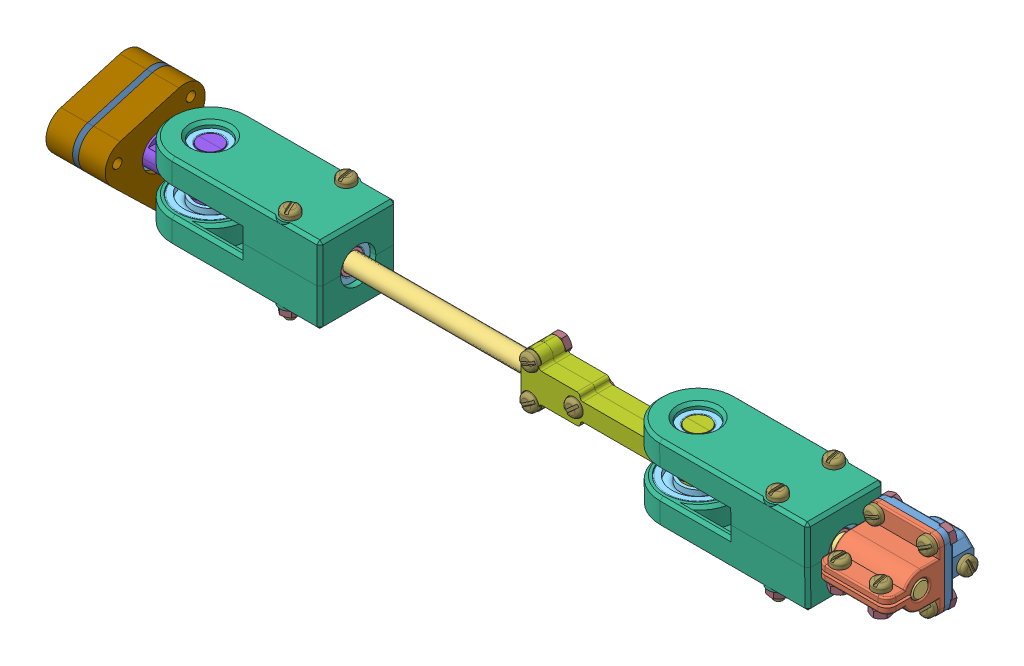
SolidWorks assembly Arm Assembly, configuration Default. Lengths in mm.
Overall size (279.84 48.78 47.27).
60 component instances, 13 part files, 139 mates.
Components (placement in the parent):
- Stepper Shaft Rod Mount - V1-1: Stepper Shaft Rod Mount - V1 [Default] x (-1 0 0) z (0 -1 0) size (24 11 24)
- Rod Holder - V1-1: Rod Holder - V1 [Default] at (12 0 2) x (0 -1 0) z (0 0 -1) size (24 24.06 19.45)
- Arm Rod - V1-1: Arm Rod - V1 [Lower Rod] at (-13 0 8) size (50 6 6)
- Bearing Rod Clamp - V2-1: Bearing Rod Clamp - V2 [Default] at (-26.6 0 8) size (25.8 10 10)
- instrument ball bearing_68_am-1: instrument ball bearing_68_am [AFBMA 12.1.4.1 - 0080-22 - 8,SI,NC,8_68] at (-34.9 0 8) x (1 0 0) z (0 -0.008393 0.999965) size (7 22 22)
- instrument ball bearing_68_am-2: instrument ball bearing_68_am [AFBMA 12.1.4.1 - 0080-22 - 8,SI,NC,8_68] at (-18.7 0 8) x (1 0 0) z (0 -0.008393 0.999965) size (7 22 22)
- Arm Joint - V1-1: Arm Joint - V1 [Default] at (-26.8 -12.9995 7.8909) x (1 0 0) z (0 -0.008393 0.999965) size (63 18.02 26)
- instrument ball bearing_68_am-3: instrument ball bearing_68_am [AFBMA 12.1.4.1 - 0080-22 - 8,SI,NC,8_68] at (-63.3 -7.4997 7.9371) x (0 -0.999965 -0.008393) z (0 -0.008393 0.999965) size (7 22 22)
- instrument ball bearing_68_am-4: instrument ball bearing_68_am [AFBMA 12.1.4.1 - 0080-22 - 8,SI,NC,8_68] at (-63.3 7.4997 8.0629) x (0 0.999965 0.008393) z (0 0.008393 -0.999965) size (7 22 22)
- Arm Joint - V1-2: Arm Joint - V1 [Default] at (-26.8 12.9995 8.1091) x (1 0 0) z (0 0.008393 -0.999965) size (63 18.02 26)
- Arm Bearing Joint Inner - V1-1: Arm Bearing Joint Inner - V1 [Bottom] at (-63.3 0 8) x (-1 -0.000006 0.000733) z (0 -0.999965 -0.008393) size (60 5 22)
- Arm Bearing Joint Inner - V1-2: Arm Bearing Joint Inner - V1 [Top] at (-63.3 0 8) x (-1 -0.000006 0.000733) z (0 0.999965 0.008393) size (60 5 22)
- Arm Rod - V1-2: Arm Rod - V1 [Upper Rod] at (-153.3 -0.0006 8.066) x (1 0.000006 -0.000733) z (0.000733 -0.008393 0.999965) size (100 6 6)
- Bearing Rod Clamp - V2-2: Bearing Rod Clamp - V2 [Default] at (-191.9 -0.0008 8.0942) x (1 0.000006 -0.000733) z (0.000733 -0.008393 0.999965) size (25.8 10 10)
- Arm Joint - V1-3: Arm Joint - V1 [Default] at (-191.9 12.9992 8.1007) x (1 0.000006 -0.000733) z (-0.000733 0.000495 -1) size (63 18.02 26)
- Arm Joint - V1-4: Arm Joint - V1 [Default] at (-191.8999 -13.0008 8.0878) x (1 0.000006 -0.000733) z (0.000733 -0.000495 1) size (63 18.02 26)
- instrument ball bearing_68_am-5: instrument ball bearing_68_am [AFBMA 12.1.4.1 - 0080-22 - 8,SI,NC,8_68] at (-200 -0.0008 8.1002) x (1 0.000006 -0.000733) z (0.000733 -0.000495 1) size (7 22 22)
- instrument ball bearing_68_am-6: instrument ball bearing_68_am [AFBMA 12.1.4.1 - 0080-22 - 8,SI,NC,8_68] at (-184 -0.0007 8.0885) x (1 0.000006 -0.000733) z (0.000733 -0.000495 1) size (7 22 22)
- instrument ball bearing_68_am-7: instrument ball bearing_68_am [AFBMA 12.1.4.1 - 0080-22 - 8,SI,NC,8_68] at (-228.3999 -7.501 8.1173) x (0.000006 -1 -0.000495) z (0.000733 -0.000495 1) size (7 22 22)
- instrument ball bearing_68_am-8: instrument ball bearing_68_am [AFBMA 12.1.4.1 - 0080-22 - 8,SI,NC,8_68] at (-228.4 7.499 8.1247) x (-0.000006 1 0.000495) z (-0.000733 0.000495 -1) size (7 22 22)
- End Effector Mount Inner - V1-1: End Effector Mount Inner - V1 [Bottom] at (-228.4 -0.001 8.121) x (-0.999996 -0.000007 0.002957) z (0.000006 -1 -0.000495) size (40 5 22)
- End Effector Mount Inner - V1-2: End Effector Mount Inner - V1 [Top] at (-228.4 -0.001 8.121) x (-0.999996 -0.000007 0.002957) z (-0.000006 1 0.000495) size (40 5 22)
- End Effector Mount - V1-1: End Effector Mount - V1 [Default] at (-245.3999 -0.0011 8.1713) x (-0.002064 0.717902 -0.696141) z (0.002118 0.696144 0.717899) size (32 9 34.78)
- End Effector Mount - V1-2: End Effector Mount - V1 [Default] at (-265.3998 -0.0013 8.2304) x (-0.000802 -0.96183 -0.273648) z (0.002847 -0.273649 0.961825) size (32 9 34.78)
- End Effector Mount Divider - V1-1: End Effector Mount Divider - V1 [Default] at (-256.3998 -0.0012 8.2038) x (-0.000802 -0.96183 -0.273648) z (0.002847 -0.273649 0.961825) size (32 2 34.78)
- End Effector Mount Clip - V1-1: End Effector Mount Clip - V1 [Default] at (-254.5998 -0.0012 8.1985) x (0.000006 -1 -0.000495) z (-0.002957 0.000495 -0.999996) size (10 1.8 9.18)
- instrument ball bearing_68_am-9: instrument ball bearing_68_am [AFBMA 12.1.4.1 - 0080-22 - 8,SI,NC,8_68] at (-250.8999 -0.0012 8.1875) x (0.999996 0.000007 -0.002957) z (0.002118 0.696144 0.717899) size (7 22 22)
- instrument ball bearing_68_am-10: instrument ball bearing_68_am [AFBMA 12.1.4.1 - 0080-22 - 8,SI,NC,8_68] at (-259.8998 -0.0012 8.2141) x (-0.999996 -0.000007 0.002957) z (0.002847 -0.273649 0.961825) size (7 22 22)
- pan slot head_am-23: pan slot head_am [B18.6.7M - M3 x 0.5 x 30 Slotted PHMS --30C] at (-26.8 15.3197 17.6289) x (0 -0.999965 -0.008393) z (0 -0.008393 0.999965) size (32.48 5.6 5.6)
- pan slot head_am-24: pan slot head_am [B18.6.7M - M3 x 0.5 x 30 Slotted PHMS --30C] at (-26.8 15.4792 -1.3704) x (0 -0.999965 -0.008393) z (0.188455 -0.008242 0.982047) size (32.48 5.6 5.6)
- pan slot head_am-26: pan slot head_am [B18.6.7M - M3 x 0.5 x 6 Slotted PHMS --6C] at (-9 9 4.4) x (0 0 -1) z (0.923728 0.383049 0) size (8.48 5.6 5.6)
- pan slot head_am-27: pan slot head_am [B18.6.7M - M3 x 0.5 x 6 Slotted PHMS --6C] at (9 9 4.4) x (0 0 -1) z (0.85131 0.524663 0) size (8.48 5.6 5.6)
- pan slot head_am-29: pan slot head_am [B18.6.7M - M3 x 0.5 x 6 Slotted PHMS --6C] at (-9 -9 4.4) x (0 0 -1) z (0.777574 0.628792 0) size (8.48 5.6 5.6)
- pan slot head_am-31: pan slot head_am [B18.6.7M - M3 x 0.5 x 6 Slotted PHMS --6C] at (9 -9 4.4) x (0 0 -1) z (0.715577 0.698533 0) size (8.48 5.6 5.6)
- pan slot head_am-33: pan slot head_am [B18.6.7M - M3 x 0.5 x 8 Slotted PHMS --8C] at (-7 4.9 16.4544) x (0 -1 0) z (0 0 1) size (10.48 5.6 5.6)
- pan slot head_am-34: pan slot head_am [B18.6.7M - M3 x 0.5 x 8 Slotted PHMS --8C] at (7 4.9 16.4544) x (0 -1 0) z (0.188455 0 0.982082) size (10.48 5.6 5.6)
- pan slot head_am-36: pan slot head_am [B18.6.7M - M3 x 0.5 x 10 Slotted PHMS --10C] at (-115.2953 5.9458 14.4882) x (-0.000733 0.008393 -0.999965) z (0.917109 0.398627 0.002673) size (12.48 5.6 5.6)
- pan slot head_am-37: pan slot head_am [B18.6.7M - M3 x 0.5 x 10 Slotted PHMS --10C] at (-115.2953 -6.0538 14.3875) x (-0.000733 0.008393 -0.999965) z (0.83264 0.553799 0.004038) size (12.48 5.6 5.6)
- pan slot head_am-39: pan slot head_am [B18.6.7M - M3 x 0.5 x 10 Slotted PHMS --10C] at (-100.2953 -0.0539 14.4269) x (-0.000733 0.008393 -0.999965) z (0.746211 0.665691 0.00504) size (12.48 5.6 5.6)
- pan slot head_am-41: pan slot head_am [B18.6.7M - M3 x 0.5 x 10 Slotted PHMS --10C] at (-63.2953 -0.0537 14.3998) x (-0.000733 0.008393 -0.999965) z (0.67374 0.738946 0.005708) size (12.48 5.6 5.6)
- pan slot head_am-43: pan slot head_am [B18.6.7M - M3 x 0.5 x 30 Slotted PHMS --30C] at (-191.907 15.4039 -1.3981) x (0.000006 -1 -0.000495) z (0.153233 -0.000489 0.98819) size (32.48 5.6 5.6)
- pan slot head_am-45: pan slot head_am [B18.6.7M - M3 x 0.5 x 30 Slotted PHMS --30C] at (-191.8931 15.3945 17.6019) x (0.000006 -1 -0.000495) z (0.402815 -0.000451 0.915281) size (32.48 5.6 5.6)
- hex nut style 1_am-1: hex nut style 1_am [B18.2.4.1M - Hex nut, Style 1,  M3 x 0.5 --D-N] at (-7 -4.9 16.4544) x (1 0 0) z (0 -1 0) size (5.5 6.35 2.4)
- hex nut style 1_am-2: hex nut style 1_am [B18.2.4.1M - Hex nut, Style 1,  M3 x 0.5 --D-N] at (7 -4.9 16.4544) x (0.982082 0 -0.188455) z (0 -1 0) size (5.5 6.35 2.4)
- hex nut style 1_am-4: hex nut style 1_am [B18.2.4.1M - Hex nut, Style 1,  M3 x 0.5 --D-N] at (-26.8 -15.4792 17.3704) x (0.918365 0.003321 -0.39572) z (0 -0.999965 -0.008393) size (5.5 6.35 2.4)
- hex nut style 1_am-6: hex nut style 1_am [B18.2.4.1M - Hex nut, Style 1,  M3 x 0.5 --D-N] at (-26.8 -15.3197 -1.6289) x (0.8 0.005036 -0.599979) z (0 -0.999965 -0.008393) size (5.5 6.35 2.4)
- hex nut style 1_am-8: hex nut style 1_am [B18.2.4.1M - Hex nut, Style 1,  M3 x 0.5 --D-N] at (-191.8929 -15.4055 17.5866) x (0.628342 0.000389 -0.777937) z (0.000006 -1 -0.000495) size (5.5 6.35 2.4)
- hex nut style 1_am-10: hex nut style 1_am [B18.2.4.1M - Hex nut, Style 1,  M3 x 0.5 --D-N] at (-191.9068 -15.3961 -1.4134) x (0.466897 0.000441 -0.884312) z (0.000006 -1 -0.000495) size (5.5 6.35 2.4)
- hex nut style 1_am-12: hex nut style 1_am [B18.2.4.1M - Hex nut, Style 1,  M3 x 0.5 --D-N] at (-9 -9 -2) x (-0.707107 0.707107 0) z (0 0 1) size (5.5 6.35 2.4)
- hex nut style 1_am-13: hex nut style 1_am [B18.2.4.1M - Hex nut, Style 1,  M3 x 0.5 --D-N] at (9 -9 -2) x (-0.965926 0.258819 0) z (0 0 1) size (5.5 6.35 2.4)
- hex nut style 1_am-15: hex nut style 1_am [B18.2.4.1M - Hex nut, Style 1,  M3 x 0.5 --D-N] at (-9 9 -2) x (0.707107 0.707107 0) z (0 0 1) size (5.5 6.35 2.4)
- hex nut style 1_am-17: hex nut style 1_am [B18.2.4.1M - Hex nut, Style 1,  M3 x 0.5 --D-N] at (9 9 -2) x (-0.258819 -0.965926 0) z (0 0 1) size (5.5 6.35 2.4)
- hex nut style 1_am-19: hex nut style 1_am [B18.2.4.1M - Hex nut, Style 1,  M3 x 0.5 --D-N] at (-115.3029 -5.9665 3.9879) x (-0.866025 0.499977 0.004831) z (0.000733 -0.008393 0.999965) size (5.5 6.35 2.4)
- hex nut style 1_am-21: hex nut style 1_am [B18.2.4.1M - Hex nut, Style 1,  M3 x 0.5 --D-N] at (-115.3029 6.033 4.0886) x (0.866025 -0.499977 -0.004831) z (0.000733 -0.008393 0.999965) size (5.5 6.35 2.4)
- hex nut style 1_am-23: hex nut style 1_am [B18.2.4.1M - Hex nut, Style 1,  M3 x 0.5 --D-N] at (-100.3029 0.0333 4.0273) x (0.5 -0.865992 -0.007635) z (0.000733 -0.008393 0.999965) size (5.5 6.35 2.4)
- hex nut style 1_am-25: hex nut style 1_am [B18.2.4.1M - Hex nut, Style 1,  M3 x 0.5 --D-N] at (-63.3029 0.0336 4.0001) x (-0.5 -0.865998 -0.006902) z (0.000733 -0.008393 0.999965) size (5.5 6.35 2.4)
- hex nut style 1_am-27: hex nut style 1_am [B18.2.4.1M - Hex nut, Style 1,  M3 x 0.5 --D-N] at (6.2 0 -7) x (0 -0.866025 0.5) z (1 0 0) size (5.5 6.35 2.4)
- pan slot head_am-48: pan slot head_am [B18.6.7M - M3 x 0.5 x 10 Slotted PHMS --10C] at (14.3 0 -7) x (-1 0 0) z (0 -0.924225 -0.381849) size (12.48 5.6 5.6)
- pan slot head_am-49: pan slot head_am [B18.6.7M - M3 x 0.5 x 10 Slotted PHMS --10N] at (-228.381 -0.0042 14.521) x (-0.002957 0.000495 -0.999996) z (0.999996 0.000497 -0.002957) size (12.4 5.6 5.6)
- hex nut style 1_am-29: hex nut style 1_am [B18.2.4.1M - Hex nut, Style 1,  M3 x 0.5 --D-N] at (-228.4189 0.0022 1.721) x (-0.999996 -0.000007 0.002957) z (-0.002957 0.000495 -0.999996) size (5.5 6.35 2.4)
Mates (geometry in assembly coordinates):
- Coincident4: coincident: plane of Stepper Shaft Rod Mount - V1-1 through (0 0 0) normal (0 0 -1); plane of assembly through (0 0 0) normal (0 0 1)
- Coincident5: coincident: plane of Stepper Shaft Rod Mount - V1-1 through (0 0 0) normal (0 -1 0); plane of assembly through (0 0 0) normal (0 1 0)
- Coincident9: coincident anti-aligned: plane of Stepper Shaft Rod Mount - V1-1 through (0 0 0) normal (-1 0 0); plane of assembly through (0 0 0) normal (1 0 0)
- Coincident10: coincident anti-aligned: plane of Stepper Shaft Rod Mount - V1-1 through (0 0 0) normal (0 0 1); plane of Rod Holder - V1-1 through (12 0 0) normal (0 0 -1)
- Concentric2: concentric: cylinder of Stepper Shaft Rod Mount - V1-1 through (-9 -9 0) axis (0 0 -1) radius 1.6; cylinder of Rod Holder - V1-1 through (-9 -9 -1) axis (0 0 1) radius 1.6
- Concentric3: concentric: cylinder of Stepper Shaft Rod Mount - V1-1 through (9 9 0) axis (0 0 -1) radius 1.6; cylinder of Rod Holder - V1-1 through (9 9 -1) axis (0 0 1) radius 1.6
- Concentric4: concentric: cylinder of Rod Holder - V1-1 through (-12 0 8) axis (1 0 0) radius 3; cylinder of Arm Rod - V1-1 through (12 0 8) axis (-1 0 0) radius 3
- Coincident11: coincident: plane of Rod Holder - V1-1 through (12 0 8) normal (1 0 0); plane of Arm Rod - V1-1 through (12 0 8) normal (1 0 0)
- Coincident12: coincident anti-aligned: plane of Arm Rod - V1-1 through (-38 0 8) normal (-1 0 0); plane of Bearing Rod Clamp - V2-1 through (-38 0 8) normal (1 0 0)
- Concentric5: concentric aligned: cylinder of Arm Rod - V1-1 through (12 0 8) axis (-1 0 0) radius 3; cylinder of Bearing Rod Clamp - V2-1 through (-38 0 8) axis (-1 0 0) radius 3.1
- Concentric6: concentric anti-aligned: cylinder of instrument ball bearing_68_am-1 through (-55.5375 0 8) axis (1 0 0) radius 11; cylinder of Arm Joint - V1-1 through (-31.2 0 8) axis (-1 0 0) radius 11.1
- Concentric7: concentric aligned: cylinder of instrument ball bearing_68_am-2 through (-39.3375 0 8) axis (1 0 0) radius 11; cylinder of Arm Joint - V1-1 through (-22.4 0 8) axis (1 0 0) radius 11.1
- Coincident13: coincident anti-aligned: plane of instrument ball bearing_68_am-2 through (-15.2 10.6996 8.0898) normal (1 0 0); plane of Arm Joint - V1-1 through (-15.2 0 8) normal (-1 0 0)
- Coincident14: coincident anti-aligned: plane of instrument ball bearing_68_am-1 through (-38.4 8.8997 8.0747) normal (-1 0 0); plane of Arm Joint - V1-1 through (-38.4 0 8) normal (1 0 0)
- Concentric8: concentric anti-aligned: cylinder of Bearing Rod Clamp - V2-1 through (-38 0 8) axis (-1 0 0) radius 3.9; cylinder of instrument ball bearing_68_am-1 through (-55.5375 0 8) axis (1 0 0) radius 4
- Coincident15: coincident aligned: plane of Bearing Rod Clamp - V2-1 through (-15.2 0 4.1) normal (1 0 0); plane of instrument ball bearing_68_am-2 through (-15.2 4.2998 8.0361) normal (1 0 0)
- Concentric9: concentric anti-aligned: cylinder of Arm Joint - V1-1 through (-63.3 -10.9996 7.9077) axis (0 0.999965 0.008393) radius 11.1; cylinder of instrument ball bearing_68_am-3 through (-63.3 13.137 8.1103) axis (0 -0.999965 -0.008393) radius 11
- Coincident16: coincident anti-aligned: plane of Arm Joint - V1-1 through (-63.3 -10.9996 7.9077) normal (0 0.999965 0.008393); plane of instrument ball bearing_68_am-3 through (-52.6 -10.9996 7.9077) normal (0 -0.999965 -0.008393)
- Concentric10: concentric anti-aligned: cylinder of instrument ball bearing_68_am-4 through (-63.3 -13.137 7.8897) axis (0 0.999965 0.008393) radius 11; cylinder of Arm Joint - V1-2 through (-63.3 10.9996 8.0923) axis (0 -0.999965 -0.008393) radius 11.1
- Coincident17: coincident anti-aligned: plane of instrument ball bearing_68_am-4 through (-52.6 10.9996 8.0923) normal (0 0.999965 0.008393); plane of Arm Joint - V1-2 through (-63.3 10.9996 8.0923) normal (0 -0.999965 -0.008393)
- Coincident18: coincident anti-aligned: plane of Arm Bearing Joint Inner - V1-1 through (-63.3 0 8) normal (0.000733 -0.008393 0.999965); plane of Arm Bearing Joint Inner - V1-2 through (-63.3 0 8) normal (-0.000733 0.008393 -0.999965)
- Coincident19: coincident aligned: plane of Arm Bearing Joint Inner - V1-1 through (-118.3 -0.0003 8.0403) normal (-1 -0.000006 0.000733); plane of Arm Bearing Joint Inner - V1-2 through (-118.3 -0.0003 8.0403) normal (-1 -0.000006 0.000733)
- Coincident20: coincident aligned: plane of Arm Bearing Joint Inner - V1-1 through (-58.3037 3.0419 3.0217) normal (0 0.999965 0.008393); plane of Arm Bearing Joint Inner - V1-2 through (-58.2963 2.958 13.0213) normal (0 0.999965 0.008393)
- Concentric11: concentric anti-aligned: cylinder of instrument ball bearing_68_am-3 through (-63.3 13.137 8.1103) axis (0 -0.999965 -0.008393) radius 4; cylinder of Arm Bearing Joint Inner - V1-2 through (-63.3 -10.9996 7.9077) axis (0 0.999965 0.008393) radius 3.9
- Coincident21: coincident anti-aligned: plane of instrument ball bearing_68_am-3 through (-57.2 -3.9999 7.9664) normal (0 0.999965 0.008393); plane of Arm Bearing Joint Inner - V1-1 through (-63.3 -3.9999 7.9664) normal (0 -0.999965 -0.008393)
- Coincident22: coincident aligned: plane of Arm Joint - V1-1 through (-40.3 -11.1087 20.9072) normal (0 -0.008393 0.999965); plane of Arm Joint - V1-2 through (-40.3 10.8905 21.0919) normal (0 -0.008393 0.999965)
- Coincident23: coincident aligned: plane of Arm Joint - V1-1 through (-13.3 -11.1087 20.9072) normal (1 0 0); plane of Arm Joint - V1-2 through (-13.3 11.1087 -4.9072) normal (1 0 0)
- Coincident24: coincident anti-aligned: plane of Arm Joint - V1-1 through (-26.8 0 8) normal (0 0.999965 0.008393); plane of Arm Joint - V1-2 through (-26.8 0 8) normal (0 -0.999965 -0.008393)
- Concentric12: concentric aligned: cylinder of Arm Bearing Joint Inner - V1-2 through (-103.3 -0.0002 8.0293) axis (-1 -0.000006 0.000733) radius 3; cylinder of Arm Rod - V1-2 through (-103.3 -0.0002 8.0293) axis (-1 -0.000006 0.000733) radius 3
- Coincident25: coincident anti-aligned: plane of Arm Bearing Joint Inner - V1-2 through (-103.3 -0.0002 8.0293) normal (-1 -0.000006 0.000733); plane of Arm Rod - V1-2 through (-103.3 -0.0002 8.0293) normal (1 0.000006 -0.000733)
- Concentric13: concentric aligned: cylinder of Arm Rod - V1-2 through (-103.3 -0.0002 8.0293) axis (-1 -0.000006 0.000733) radius 3; cylinder of Bearing Rod Clamp - V2-2 through (-203.3 -0.0009 8.1026) axis (-1 -0.000006 0.000733) radius 3.1
- Coincident26: coincident anti-aligned: plane of Arm Rod - V1-2 through (-203.3 -0.0009 8.1026) normal (-1 -0.000006 0.000733); plane of Bearing Rod Clamp - V2-2 through (-203.3 -0.0009 8.1026) normal (1 0.000006 -0.000733)
- Concentric19: concentric anti-aligned: cylinder of Arm Joint - V1-4 through (-196.3 -0.0008 8.0975) axis (-1 -0.000006 0.000733) radius 11.1; cylinder of instrument ball bearing_68_am-5 through (-220.6375 -0.001 8.1153) axis (1 0.000006 -0.000733) radius 11
- Coincident35: coincident anti-aligned: plane of Arm Joint - V1-4 through (-203.5 -0.0009 8.1027) normal (1 0.000006 -0.000733); plane of instrument ball bearing_68_am-5 through (-203.5 8.8991 8.1071) normal (-1 -0.000006 0.000733)
- Concentric20: concentric aligned: cylinder of Arm Joint - V1-4 through (-187.5 -0.0008 8.091) axis (1 0.000006 -0.000733) radius 11.1; cylinder of instrument ball bearing_68_am-6 through (-204.6375 -0.0009 8.1036) axis (1 0.000006 -0.000733) radius 11
- Coincident36: coincident anti-aligned: plane of Arm Joint - V1-4 through (-187.5 -0.0008 8.091) normal (1 0.000006 -0.000733); plane of instrument ball bearing_68_am-6 through (-187.5 8.8992 8.0954) normal (-1 -0.000006 0.000733)
- Concentric21: concentric anti-aligned: cylinder of Arm Joint - V1-4 through (-228.3999 -11.001 8.1155) axis (-0.000006 1 0.000495) radius 11.1; cylinder of instrument ball bearing_68_am-7 through (-228.4 13.1365 8.1275) axis (0.000006 -1 -0.000495) radius 11
- Coincident37: coincident anti-aligned: plane of Arm Joint - V1-4 through (-228.3999 -11.001 8.1155) normal (-0.000006 1 0.000495); plane of instrument ball bearing_68_am-7 through (-217.6999 -11.0009 8.1077) normal (0.000006 -1 -0.000495)
- Concentric22: concentric anti-aligned: cylinder of Arm Joint - V1-3 through (-228.4 10.999 8.1264) axis (0.000006 -1 -0.000495) radius 11.1; cylinder of instrument ball bearing_68_am-8 through (-228.3999 -13.1385 8.1145) axis (-0.000006 1 0.000495) radius 11
- Coincident38: coincident anti-aligned: plane of Arm Joint - V1-3 through (-228.4 10.999 8.1264) normal (0.000006 -1 -0.000495); plane of instrument ball bearing_68_am-8 through (-217.7 10.999 8.1186) normal (-0.000006 1 0.000495)
- Concentric23: concentric anti-aligned: cylinder of Bearing Rod Clamp - V2-2 through (-203.3 -0.0009 8.1026) axis (-1 -0.000006 0.000733) radius 3.9; cylinder of instrument ball bearing_68_am-5 through (-220.6375 -0.001 8.1153) axis (1 0.000006 -0.000733) radius 4
- Coincident39: coincident aligned: plane of Bearing Rod Clamp - V2-2 through (-180.5028 0.032 4.186) normal (1 0.000006 -0.000733); plane of instrument ball bearing_68_am-6 through (-180.5 4.2993 8.088) normal (1 0.000006 -0.000733)
- Coincident40: coincident anti-aligned: plane of End Effector Mount Inner - V1-1 through (-228.4 -0.001 8.121) normal (0.002957 -0.000495 0.999996); plane of End Effector Mount Inner - V1-2 through (-228.4 -0.001 8.121) normal (-0.002957 0.000495 -0.999996)
- Coincident41: coincident aligned: plane of End Effector Mount Inner - V1-1 through (-223.4147 -2.9985 3.1047) normal (0.000006 -1 -0.000495); plane of End Effector Mount Inner - V1-2 through (-223.3852 -3.0035 13.1047) normal (0.000006 -1 -0.000495)
- Coincident42: coincident aligned: plane of End Effector Mount Inner - V1-1 through (-263.3998 -0.0013 8.2245) normal (-0.999996 -0.000007 0.002957); plane of End Effector Mount Inner - V1-2 through (-263.3998 -0.0013 8.2245) normal (-0.999996 -0.000007 0.002957)
- Concentric24: concentric anti-aligned: cylinder of instrument ball bearing_68_am-7 through (-228.4 13.1365 8.1275) axis (0.000006 -1 -0.000495) radius 4; cylinder of End Effector Mount Inner - V1-2 through (-228.3999 -11.001 8.1155) axis (-0.000006 1 0.000495) radius 3.9
- Coincident43: coincident anti-aligned: plane of instrument ball bearing_68_am-7 through (-222.2999 -4.001 8.1145) normal (-0.000006 1 0.000495); plane of End Effector Mount Inner - V1-2 through (-228.3999 -4.001 8.119) normal (0.000006 -1 -0.000495)
- Coincident44: coincident aligned: plane of Arm Joint - V1-3 through (-205.4096 11.0056 -4.8904) normal (-0.000733 0.000495 -1); plane of Arm Joint - V1-4 through (-205.4094 -10.9944 -4.9013) normal (-0.000733 0.000495 -1)
- Coincident45: coincident aligned: plane of Arm Joint - V1-3 through (-178.4096 11.0057 -4.9102) normal (1 0.000006 -0.000733); plane of Arm Joint - V1-4 through (-178.3904 -11.0071 21.0789) normal (1 0.000006 -0.000733)
- Coincident46: coincident anti-aligned: plane of Arm Joint - V1-3 through (-191.9 -0.0008 8.0942) normal (0.000006 -1 -0.000495); plane of Arm Joint - V1-4 through (-191.9 -0.0008 8.0942) normal (-0.000006 1 0.000495)
- Concentric25: concentric anti-aligned: cylinder of End Effector Mount Inner - V1-2 through (-263.3998 -0.0013 8.2245) axis (0.999996 0.000007 -0.002957) radius 3.9; cylinder of End Effector Mount Clip - V1-1 through (-254.5998 -0.0012 8.1985) axis (-0.999996 -0.000007 0.002957) radius 4
- Parallel4: parallel anti-aligned: plane of End Effector Mount Inner - V1-2 through (-254.385 -2.9037 13.1964) normal (0.000006 -1 -0.000495); plane of End Effector Mount Clip - V1-1 through (-254.592 -3.0025 10.8427) normal (-0.000006 1 0.000495)
- Coincident48: coincident anti-aligned: plane of End Effector Mount Inner - V1-2 through (-256.385 -2.9037 13.2023) normal (0.999996 0.000007 -0.002957); plane of End Effector Mount Clip - V1-1 through (-256.3998 -0.0012 8.2038) normal (-0.999996 -0.000007 0.002957)
- Concentric26: concentric anti-aligned: cylinder of End Effector Mount - V1-1 through (-247.3999 -0.0012 8.1772) axis (-0.999996 -0.000007 0.002957) radius 11.1; cylinder of instrument ball bearing_68_am-9 through (-271.5373 -0.0013 8.2486) axis (0.999996 0.000007 -0.002957) radius 11
- Coincident49: coincident anti-aligned: plane of End Effector Mount - V1-1 through (-247.3999 -0.0012 8.1772) normal (-0.999996 -0.000007 0.002957); plane of instrument ball bearing_68_am-9 through (-247.422 7.6804 0.7285) normal (0.999996 0.000007 -0.002957)
- Concentric27: concentric anti-aligned: cylinder of End Effector Mount - V1-2 through (-263.3998 -0.0013 8.2245) axis (0.999996 0.000007 -0.002957) radius 11.1; cylinder of instrument ball bearing_68_am-10 through (-239.2624 -0.0011 8.1531) axis (-0.999996 -0.000007 0.002957) radius 11
- Coincident50: coincident anti-aligned: plane of End Effector Mount - V1-2 through (-263.3998 -0.0013 8.2245) normal (0.999996 0.000007 -0.002957); plane of instrument ball bearing_68_am-10 through (-263.4084 -10.2928 5.2965) normal (-0.999996 -0.000007 0.002957)
- Concentric28: concentric anti-aligned: cylinder of End Effector Mount - V1-2 through (-265.3998 -0.0013 8.2304) axis (0.999996 0.000007 -0.002957) radius 6; cylinder of End Effector Mount Divider - V1-1 through (-254.3998 -0.0012 8.1979) axis (-0.999996 -0.000007 0.002957) radius 6
- Coincident51: coincident aligned: plane of End Effector Mount - V1-2 through (-256.4207 -25.0088 1.089) normal (-0.002866 -0.243928 -0.969789); plane of End Effector Mount Divider - V1-1 through (-254.4207 -25.0088 1.083) normal (-0.002866 -0.243928 -0.969789)
- Coincident52: coincident anti-aligned: plane of End Effector Mount - V1-2 through (-256.3998 -0.0012 8.2038) normal (0.999996 0.000007 -0.002957); plane of End Effector Mount Divider - V1-1 through (-256.3998 -0.0012 8.2038) normal (-0.999996 -0.000007 0.002957)
- Coincident53: coincident anti-aligned: plane of End Effector Mount - V1-1 through (-254.3998 -0.0012 8.1979) normal (-0.999996 -0.000007 0.002957); plane of End Effector Mount Divider - V1-1 through (-254.3998 -0.0012 8.1979) normal (0.999996 0.000007 -0.002957)
- Concentric29: concentric anti-aligned: cylinder of End Effector Mount - V1-1 through (-245.3999 -0.0011 8.1713) axis (-0.999996 -0.000007 0.002957) radius 6; cylinder of End Effector Mount - V1-2 through (-265.3998 -0.0013 8.2304) axis (0.999996 0.000007 -0.002957) radius 6
- Coincident54: coincident aligned: plane of End Effector Mount - V1-1 through (-254.4535 18.6642 -9.9018) normal (-0.002866 -0.243928 -0.969789); plane of End Effector Mount - V1-2 through (-256.4207 -25.0088 1.089) normal (-0.002866 -0.243928 -0.969789)
- Concentric30: concentric aligned: cylinder of End Effector Mount Inner - V1-2 through (-263.3998 -0.0013 8.2245) axis (0.999996 0.000007 -0.002957) radius 3.9; cylinder of instrument ball bearing_68_am-9 through (-271.5373 -0.0013 8.2486) axis (0.999996 0.000007 -0.002957) radius 4
- Coincident55: coincident aligned: plane of End Effector Mount Inner - V1-2 through (-263.3998 -0.0013 8.2245) normal (-0.999996 -0.000007 0.002957); plane of instrument ball bearing_68_am-10 through (-263.4033 -4.1371 7.0478) normal (-0.999996 -0.000007 0.002957)
- Concentric65: concentric anti-aligned: cylinder of Arm Joint - V1-2 through (-26.8 12.9198 17.6088) axis (0 -0.999965 -0.008393) radius 1.6; cylinder of pan slot head_am-23 through (-26.8 40.7188 17.8421) axis (0 0.999965 0.008393) radius 1.5
- Coincident90: coincident anti-aligned: plane of Arm Joint - V1-2 through (-26.8 12.9995 8.1091) normal (0 0.999965 0.008393); plane of pan slot head_am-23 through (-25.3 12.9198 17.6088) normal (0 -0.999965 -0.008393)
- Concentric66: concentric anti-aligned: cylinder of Arm Joint - V1-2 through (-26.8 13.0793 -1.3906) axis (0 -0.999965 -0.008393) radius 1.6; cylinder of pan slot head_am-24 through (-26.8 40.8783 -1.1572) axis (0 0.999965 0.008393) radius 1.5
- Coincident91: coincident anti-aligned: plane of Arm Joint - V1-2 through (-26.8 12.9995 8.1091) normal (0 0.999965 0.008393); plane of pan slot head_am-24 through (-25.3269 13.0816 -1.6732) normal (0 -0.999965 -0.008393)
- Concentric67: concentric aligned: cylinder of Rod Holder - V1-1 through (-9 9 -1) axis (0 0 1) radius 1.6; cylinder of pan slot head_am-26 through (-9 9 29.8) axis (0 0 1) radius 1.5
- Coincident92: coincident anti-aligned: plane of Rod Holder - V1-1 through (12 0 2) normal (0 0 1); plane of pan slot head_am-26 through (-9.5746 10.3856 2) normal (0 0 -1)
- Concentric68: concentric aligned: cylinder of Rod Holder - V1-1 through (9 9 -1) axis (0 0 1) radius 1.6; cylinder of pan slot head_am-27 through (9 9 29.8) axis (0 0 1) radius 1.5
- Coincident93: coincident anti-aligned: plane of Rod Holder - V1-1 through (12 0 2) normal (0 0 1); plane of pan slot head_am-27 through (8.213 10.277 2) normal (0 0 -1)
- Concentric69: concentric aligned: cylinder of Rod Holder - V1-1 through (-9 -9 -1) axis (0 0 1) radius 1.6; cylinder of pan slot head_am-29 through (-9 -9 29.8) axis (0 0 1) radius 1.5
- Coincident94: coincident anti-aligned: plane of Rod Holder - V1-1 through (12 0 2) normal (0 0 1); plane of pan slot head_am-29 through (-9.9432 -7.8336 2) normal (0 0 -1)
- Concentric70: concentric aligned: cylinder of Rod Holder - V1-1 through (9 -9 -1) axis (0 0 1) radius 1.6; cylinder of pan slot head_am-31 through (9 -9 29.8) axis (0 0 1) radius 1.5
- Coincident95: coincident anti-aligned: plane of Rod Holder - V1-1 through (12 0 2) normal (0 0 1); plane of pan slot head_am-31 through (7.9522 -7.9266 2) normal (0 0 -1)
- Concentric71: concentric anti-aligned: cylinder of Rod Holder - V1-1 through (-7 6 16.4544) axis (0 -1 0) radius 1.6; cylinder of pan slot head_am-33 through (-7 30.3 16.4544) axis (0 1 0) radius 1.5
- Coincident96: coincident anti-aligned: plane of Rod Holder - V1-1 through (-12 2.5 13.4544) normal (0 1 0); plane of pan slot head_am-33 through (-5.5 2.5 16.4544) normal (0 -1 0)
- Concentric72: concentric anti-aligned: cylinder of Rod Holder - V1-1 through (7 6 16.4544) axis (0 -1 0) radius 1.6; cylinder of pan slot head_am-34 through (7 30.3 16.4544) axis (0 1 0) radius 1.5
- Coincident97: coincident anti-aligned: plane of Rod Holder - V1-1 through (-12 2.5 13.4544) normal (0 1 0); plane of pan slot head_am-34 through (8.4731 2.5 16.1717) normal (0 -1 0)
- Concentric73: concentric anti-aligned: cylinder of Arm Bearing Joint Inner - V1-2 through (-115.2963 5.9575 13.0883) axis (-0.000733 0.008393 -0.999965) radius 1.6; cylinder of pan slot head_am-36 through (-115.2767 5.7326 39.8873) axis (0.000733 -0.008393 0.999965) radius 1.5
- Coincident98: coincident anti-aligned: plane of Arm Bearing Joint Inner - V1-2 through (-115.2971 5.9659 12.0883) normal (0.000733 -0.008393 0.999965); plane of pan slot head_am-36 through (-115.895 7.3415 12.1003) normal (-0.000733 0.008393 -0.999965)
- Concentric74: concentric anti-aligned: cylinder of Arm Bearing Joint Inner - V1-2 through (-115.2963 -6.0421 12.9876) axis (-0.000733 0.008393 -0.999965) radius 1.6; cylinder of pan slot head_am-37 through (-115.2767 -6.267 39.7866) axis (0.000733 -0.008393 0.999965) radius 1.5
- Coincident99: coincident anti-aligned: plane of Arm Bearing Joint Inner - V1-2 through (-115.2971 -6.0337 11.9876) normal (0.000733 -0.008393 0.999965); plane of pan slot head_am-37 through (-116.1278 -4.7848 11.9987) normal (-0.000733 0.008393 -0.999965)
- Concentric75: concentric anti-aligned: cylinder of Arm Bearing Joint Inner - V1-2 through (-100.2963 -0.0422 13.0269) axis (-0.000733 0.008393 -0.999965) radius 1.6; cylinder of pan slot head_am-39 through (-100.2767 -0.2671 39.826) axis (0.000733 -0.008393 0.999965) radius 1.5
- Coincident100: coincident anti-aligned: plane of Arm Bearing Joint Inner - V1-2 through (-100.2971 -0.0338 12.027) normal (0.000733 -0.008393 0.999965); plane of pan slot head_am-39 through (-101.2956 1.0855 12.0371) normal (-0.000733 0.008393 -0.999965)
- Concentric76: concentric anti-aligned: cylinder of Arm Bearing Joint Inner - V1-2 through (-63.2963 -0.042 12.9998) axis (-0.000733 0.008393 -0.999965) radius 1.6; cylinder of pan slot head_am-41 through (-63.2767 -0.2669 39.7989) axis (0.000733 -0.008393 0.999965) radius 1.5
- Coincident101: coincident anti-aligned: plane of Arm Bearing Joint Inner - V1-2 through (-63.2971 -0.0336 11.9999) normal (0.000733 -0.008393 0.999965); plane of pan slot head_am-41 through (-64.4055 0.977 12.0092) normal (-0.000733 0.008393 -0.999965)
- Concentric77: concentric anti-aligned: cylinder of Arm Joint - V1-3 through (-191.907 13.0039 -1.3993) axis (0.000006 -1 -0.000495) radius 1.6; cylinder of pan slot head_am-43 through (-191.9072 40.8039 -1.3855) axis (-0.000006 1 0.000495) radius 1.5
- Coincident102: coincident anti-aligned: plane of Arm Joint - V1-3 through (-191.9 12.9992 8.1007) normal (-0.000006 1 0.000495); plane of pan slot head_am-43 through (-190.4247 13.004 -1.6292) normal (0.000006 -1 -0.000495)
- Concentric78: concentric anti-aligned: cylinder of Arm Joint - V1-3 through (-191.8931 12.9945 17.6007) axis (0.000006 -1 -0.000495) radius 1.6; cylinder of pan slot head_am-45 through (-191.8932 40.7945 17.6144) axis (-0.000006 1 0.000495) radius 1.5
- Coincident103: coincident anti-aligned: plane of Arm Joint - V1-3 through (-191.9 12.9992 8.1007) normal (-0.000006 1 0.000495); plane of pan slot head_am-45 through (-190.5202 12.9948 16.9965) normal (0.000006 -1 -0.000495)
- Concentric79: concentric anti-aligned: cylinder of pan slot head_am-33 through (-7 30.3 16.4544) axis (0 1 0) radius 1.5; cylinder of hex nut style 1_am-1 through (-7 -2.5 16.4544) axis (0 -1 0) radius 1.25
- Coincident104: coincident anti-aligned: plane of Rod Holder - V1-1 through (-12 -2.5 13.4544) normal (0 -1 0); plane of hex nut style 1_am-1 through (-7 -2.5 19.6298) normal (0 1 0)
- Concentric80: concentric anti-aligned: cylinder of pan slot head_am-34 through (7 30.3 16.4544) axis (0 1 0) radius 1.5; cylinder of hex nut style 1_am-2 through (7 -2.5 16.4544) axis (0 -1 0) radius 1.25
- Coincident105: coincident anti-aligned: plane of Rod Holder - V1-1 through (-12 -2.5 13.4544) normal (0 -1 0); plane of hex nut style 1_am-2 through (7.5984 -2.5 19.5729) normal (0 1 0)
- Concentric81: concentric anti-aligned: cylinder of pan slot head_am-23 through (-26.8 40.7188 17.8421) axis (0 0.999965 0.008393) radius 1.5; cylinder of hex nut style 1_am-4 through (-26.8 -13.0793 17.3906) axis (0 -0.999965 -0.008393) radius 1.25
- Coincident106: coincident anti-aligned: plane of Arm Joint - V1-1 through (-26.8 -12.9995 7.8909) normal (0 -0.999965 -0.008393); plane of hex nut style 1_am-4 through (-25.5434 -13.1037 20.3067) normal (0 0.999965 0.008393)
- Concentric82: concentric anti-aligned: cylinder of pan slot head_am-24 through (-26.8 40.8783 -1.1572) axis (0 0.999965 0.008393) radius 1.5; cylinder of hex nut style 1_am-6 through (-26.8 -12.9198 -1.6088) axis (0 -0.999965 -0.008393) radius 1.25
- Coincident107: coincident anti-aligned: plane of Arm Joint - V1-1 through (-26.8 -12.9995 7.8909) normal (0 -0.999965 -0.008393); plane of hex nut style 1_am-6 through (-24.8947 -12.9411 0.9315) normal (0 0.999965 0.008393)
- Concentric83: concentric anti-aligned: cylinder of pan slot head_am-45 through (-191.8932 40.7945 17.6144) axis (-0.000006 1 0.000495) radius 1.5; cylinder of hex nut style 1_am-8 through (-191.8929 -13.0055 17.5878) axis (0.000006 -1 -0.000495) radius 1.25
- Coincident108: coincident anti-aligned: plane of Arm Joint - V1-4 through (-191.8999 -13.0008 8.0878) normal (0.000006 -1 -0.000495); plane of hex nut style 1_am-8 through (-189.4226 -13.0065 19.5831) normal (-0.000006 1 0.000495)
- Concentric84: concentric anti-aligned: cylinder of pan slot head_am-43 through (-191.9072 40.8039 -1.3855) axis (-0.000006 1 0.000495) radius 1.5; cylinder of hex nut style 1_am-10 through (-191.9069 -12.9961 -1.4122) axis (0.000006 -1 -0.000495) radius 1.25
- Coincident109: coincident anti-aligned: plane of Arm Joint - V1-4 through (-191.8999 -13.0008 8.0878) normal (0.000006 -1 -0.000495); plane of hex nut style 1_am-10 through (-189.0988 -12.9968 0.0704) normal (-0.000006 1 0.000495)
- Concentric85: concentric aligned: cylinder of pan slot head_am-29 through (-9 -9 29.8) axis (0 0 1) radius 1.5; cylinder of hex nut style 1_am-12 through (-9 -9 -4.4) axis (0 0 1) radius 1.25
- Parallel5: parallel anti-aligned: plane of Stepper Shaft Rod Mount - V1-1 through (-9.8517 -5.8212 -11) normal (-0.258819 -0.965926 0); plane of hex nut style 1_am-12 through (-6.7546 -6.7546 -4.4) normal (0.258819 0.965926 0)
- Coincident111: coincident anti-aligned: plane of Stepper Shaft Rod Mount - V1-1 through (0 0 -2) normal (0 0 -1); plane of hex nut style 1_am-12 through (-11.2454 -11.2454 -2) normal (0 0 1)
- Concentric86: concentric aligned: cylinder of pan slot head_am-31 through (9 -9 29.8) axis (0 0 1) radius 1.5; cylinder of hex nut style 1_am-13 through (9 -9 -4.4) axis (0 0 1) radius 1.25
- Parallel6: parallel anti-aligned: plane of Stepper Shaft Rod Mount - V1-1 through (9.8517 -5.8212 -11) normal (0.258819 -0.965926 0); plane of hex nut style 1_am-13 through (9.8219 -5.9328 -4.4) normal (-0.258819 0.965926 0)
- Coincident112: coincident anti-aligned: plane of Stepper Shaft Rod Mount - V1-1 through (0 0 -2) normal (0 0 -1); plane of hex nut style 1_am-13 through (8.1781 -12.0672 -2) normal (0 0 1)
- Concentric87: concentric aligned: cylinder of pan slot head_am-26 through (-9 9 29.8) axis (0 0 1) radius 1.5; cylinder of hex nut style 1_am-15 through (-9 9 -4.4) axis (0 0 1) radius 1.25
- Parallel7: parallel anti-aligned: plane of Stepper Shaft Rod Mount - V1-1 through (-6.673 6.673 -11) normal (-0.965926 0.258819 0); plane of hex nut style 1_am-15 through (-6.7546 6.7546 -4.4) normal (0.965926 -0.258819 0)
- Coincident113: coincident anti-aligned: plane of Stepper Shaft Rod Mount - V1-1 through (0 0 -2) normal (0 0 -1); plane of hex nut style 1_am-15 through (-11.2454 11.2454 -2) normal (0 0 1)
- Concentric88: concentric aligned: cylinder of pan slot head_am-27 through (9 9 29.8) axis (0 0 1) radius 1.5; cylinder of hex nut style 1_am-17 through (9 9 -4.4) axis (0 0 1) radius 1.25
- Parallel8: parallel anti-aligned: plane of Stepper Shaft Rod Mount - V1-1 through (6.673 6.673 -11) normal (0.965926 0.258819 0); plane of hex nut style 1_am-17 through (5.9328 9.8219 -4.4) normal (-0.965926 -0.258819 0)
- Coincident114: coincident anti-aligned: plane of Stepper Shaft Rod Mount - V1-1 through (0 0 -2) normal (0 0 -1); plane of hex nut style 1_am-17 through (12.0672 8.1781 -2) normal (0 0 1)
- Concentric89: concentric aligned: cylinder of pan slot head_am-37 through (-115.2767 -6.267 39.7866) axis (0.000733 -0.008393 0.999965) radius 1.5; cylinder of hex nut style 1_am-19 through (-115.3047 -5.9464 1.588) axis (0.000733 -0.008393 0.999965) radius 1.25
- Parallel9: parallel anti-aligned: plane of Arm Bearing Joint Inner - V1-1 through (-116.9484 -3.1166 4.013) normal (0 -0.999965 -0.008393); plane of hex nut style 1_am-19 through (-113.717 -3.1965 1.6099) normal (0 0.999965 0.008393)
- Coincident115: coincident anti-aligned: plane of Arm Bearing Joint Inner - V1-1 through (-63.3029 0.0336 4.0001) normal (-0.000733 0.008393 -0.999965); plane of hex nut style 1_am-19 through (-116.8906 -8.7165 3.966) normal (0.000733 -0.008393 0.999965)
- Concentric90: concentric aligned: cylinder of pan slot head_am-36 through (-115.2767 5.7326 39.8873) axis (0.000733 -0.008393 0.999965) radius 1.5; cylinder of hex nut style 1_am-21 through (-115.3047 6.0532 1.6887) axis (0.000733 -0.008393 0.999965) radius 1.25
- Parallel10: parallel anti-aligned: plane of Arm Bearing Joint Inner - V1-1 through (-113.6575 3.1831 4.0635) normal (0 0.999965 0.008393); plane of hex nut style 1_am-21 through (-116.8924 3.3033 1.6668) normal (0 -0.999965 -0.008393)
- Coincident116: coincident anti-aligned: plane of Arm Bearing Joint Inner - V1-1 through (-63.3029 0.0336 4.0001) normal (-0.000733 0.008393 -0.999965); plane of hex nut style 1_am-21 through (-113.7152 8.783 4.1105) normal (0.000733 -0.008393 0.999965)
- Concentric91: concentric aligned: cylinder of pan slot head_am-39 through (-100.2767 -0.2671 39.826) axis (0.000733 -0.008393 0.999965) radius 1.5; cylinder of hex nut style 1_am-23 through (-100.3047 0.0535 1.6273) axis (0.000733 -0.008393 0.999965) radius 1.25
- Parallel11: parallel anti-aligned: plane of Arm Bearing Joint Inner - V1-1 through (-100.3029 -3.2574 3.9996) normal (0.5 0.865998 0.006902); plane of hex nut style 1_am-23 through (-103.0547 -1.5342 1.616) normal (-0.5 -0.865998 -0.006902)
- Coincident117: coincident anti-aligned: plane of Arm Bearing Joint Inner - V1-1 through (-63.3029 0.0336 4.0001) normal (-0.000733 0.008393 -0.999965); plane of hex nut style 1_am-23 through (-97.5529 1.621 4.0386) normal (0.000733 -0.008393 0.999965)
- Concentric92: concentric aligned: cylinder of pan slot head_am-41 through (-63.2767 -0.2669 39.7989) axis (0.000733 -0.008393 0.999965) radius 1.5; cylinder of hex nut style 1_am-25 through (-63.3047 0.0537 1.6002) axis (0.000733 -0.008393 0.999965) radius 1.25
- Parallel12: parallel anti-aligned: plane of Arm Bearing Joint Inner - V1-1 through (-66.1529 -1.6118 3.9884) normal (1 0.000006 -0.000733); plane of hex nut style 1_am-25 through (-66.0547 1.6414 1.6156) normal (-1 -0.000006 0.000733)
- Coincident118: coincident anti-aligned: plane of Arm Bearing Joint Inner - V1-1 through (-63.3029 0.0336 4.0001) normal (-0.000733 0.008393 -0.999965); plane of hex nut style 1_am-25 through (-60.5529 -1.5541 3.9848) normal (0.000733 -0.008393 0.999965)
- Concentric93: concentric aligned: cylinder of Stepper Shaft Rod Mount - V1-1 through (-12.001 0 -7) axis (1 0 0) radius 1.6; cylinder of hex nut style 1_am-27 through (3.8 0 -7) axis (1 0 0) radius 1.25
- Parallel13: parallel anti-aligned: plane of Stepper Shaft Rod Mount - V1-1 through (6.2 -1.6454 -4.15) normal (0 0 -1); plane of hex nut style 1_am-27 through (3.8 1.5877 -4.25) normal (0 0 1)
- Coincident119: coincident anti-aligned: plane of Stepper Shaft Rod Mount - V1-1 through (6.2 0 0) normal (-1 0 0); plane of hex nut style 1_am-27 through (6.2 -1.5877 -9.75) normal (1 0 0)
- Concentric94: concentric aligned: cylinder of Stepper Shaft Rod Mount - V1-1 through (-12.001 0 -7) axis (1 0 0) radius 1.6; cylinder of pan slot head_am-48 through (39.7 0 -7) axis (1 0 0) radius 1.5
- Coincident120: coincident aligned: plane of Stepper Shaft Rod Mount - V1-1 through (1.9 1.7748 0) normal (-1 0 0); plane of pan slot head_am-48 through (1.9 0.5728 -8.3863) normal (-1 0 0)
- Concentric95: concentric anti-aligned: cylinder of End Effector Mount Inner - V1-2 through (-228.3852 -0.0035 13.121) axis (-0.002957 0.000495 -0.999996) radius 1.6; cylinder of pan slot head_am-49 through (-228.3059 -0.0168 39.9208) axis (0.002957 -0.000495 0.999996) radius 2.8
- Coincident121: coincident anti-aligned: plane of End Effector Mount Inner - V1-2 through (-228.3881 -0.003 12.121) normal (0.002957 -0.000495 0.999996); plane of pan slot head_am-49 through (-228.3889 1.497 12.1217) normal (-0.002957 0.000495 -0.999996)
- Concentric97: concentric anti-aligned: cylinder of End Effector Mount Inner - V1-1 through (-228.4147 0.0015 3.121) axis (0.002957 -0.000495 0.999996) radius 1.6; cylinder of hex nut style 1_am-29 through (-228.3448 -0.0102 26.7584) axis (-0.002957 0.000495 -0.999996) radius 1.5
- Coincident123: coincident anti-aligned: plane of End Effector Mount Inner - V1-1 through (-228.4118 0.001 4.121) normal (-0.002957 0.000495 -0.999996); plane of hex nut style 1_am-29 through (-228.4118 3.1764 4.1226) normal (0.002957 -0.000495 0.999996)
- Parallel14: parallel anti-aligned: plane of End Effector Mount Inner - V1-1 through (-231.2618 1.6464 4.1302) normal (0.999996 0.000007 -0.002957); plane of hex nut style 1_am-29 through (-231.1618 1.5887 4.1299) normal (-0.999996 -0.000007 0.002957)
